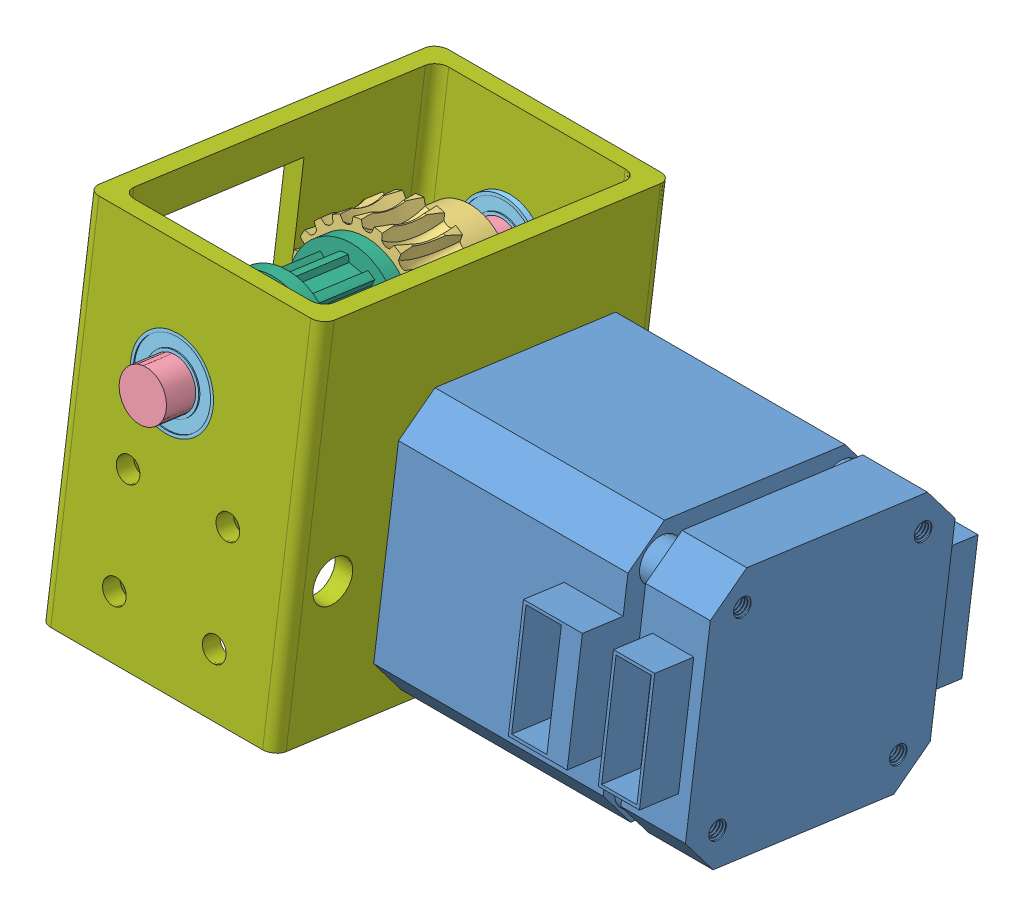
SolidWorks assembly Asm_42Driver_90Degree, configuration 默认. Lengths in mm.
Overall size (98.8 67.62 71.02).
8 component instances, 7 part files, 16 mates.
Components (placement in the parent):
- Part_42Motor-1: Part_42Motor [默认] at (65.4672 -14.0309 56.4881) x (0 0.990656 -0.136383) z (0 0.136383 0.990656) size (42 76 55.7)
- Part_Shaft_1Modulus_1Teeth_42SMotor-1: Part_Shaft_1Modulus_1Teeth_42SMotor [默认] at (-21.5328 3.9089 32.8203) x (1 0 0) z (0 0.681581 -0.731743) size (33.1 17.69 17.84)
- Part_Turbine_1Modulus_20Teeth_42SMotor-1: Part_Turbine_1Modulus_20Teeth_42SMotor [默认] at (-10.5328 22.4226 35.3187) x (0 -0.990656 0.136383) z (1 0 0) size (29.84 18 44.58)
- Part_Axis_8mm_Turbine_Rocker-1: Part_Axis_8mm_Turbine_Rocker [默认] at (-10.5328 17.922 2.627) x (0.931599 0.360092 -0.049574) z (0 0.136383 0.990656) size (8 17.7 70)
- Part_Bearing_MR148ZZ-1: Part_Bearing_MR148ZZ [默认] at (-10.5328 19.1494 11.5429) x (0 -0.136383 -0.990656) z (0.425184 0.89665 -0.123441) size (4 14 14)
- Part_Bearing_MR148ZZ-2: Part_Bearing_MR148ZZ [默认] at (-10.5328 26.7869 67.0197) x (0 -0.136383 -0.990656) z (-0.945462 0.322689 -0.044424) size (4 14 14)
- Part_SyncWheel_XL10AF_Axis_8mm-2: Part_SyncWheel_XL10AF_Axis_8mm [默认] at (-10.5328 24.2638 48.6925) x (0 -0.136383 -0.990656) z (0.128031 -0.982503 0.13526) size (16 19 19)
- Part_Flange_42Motor-1: Part_Flange_42Motor [默认] at (-27.5328 -22.013 13.172) x (0 0.990656 -0.136383) z (0 -0.136383 -0.990656) size (60 40 60)
Mates (geometry in assembly coordinates):
- 重合8: coincident aligned: line of Part_Shaft_1Modulus_1Teeth_42SMotor-1 through (-21.5328 3.9089 32.8203) axis (1 0 0); line of Part_Turbine_1Modulus_20Teeth_42SMotor-1 through (-29.181 3.9089 32.8203) axis (1 0 0)
- 同心5: concentric anti-aligned: cylinder of Part_Shaft_1Modulus_1Teeth_42SMotor-1 through (8.4672 3.9089 32.8203) axis (-1 0 0) radius 2.5; cylinder of Part_42Motor-1 through (-10.5328 3.9089 32.8203) axis (1 0 0) radius 2.5
- 距离7: distance = 4 mm anti-aligned: plane of Part_Shaft_1Modulus_1Teeth_42SMotor-1 through (8.4672 3.9089 32.8203) normal (1 0 0); plane of Part_42Motor-1 through (4.4672 -14.0309 56.4881) normal (-1 0 0)
- 平行6: parallel aligned: plane of Part_42Motor-1 through (12.4672 -14.3103 14.1304) normal (0 -0.136383 -0.990656); plane of Part_Turbine_1Modulus_20Teeth_42SMotor-1 through (-10.5328 21.0588 25.4121) normal (0 -0.136383 -0.990656)
- 同心6: concentric anti-aligned: cylinder of Part_Turbine_1Modulus_20Teeth_42SMotor-1 through (-10.5328 21.0588 25.4121) axis (0 0.136383 0.990656) radius 4; cylinder of Part_Axis_8mm_Turbine_Rocker-1 through (-10.5328 27.4688 71.9729) axis (0 -0.136383 -0.990656) radius 4
- 同心7: concentric anti-aligned: cylinder of Part_Axis_8mm_Turbine_Rocker-1 through (-10.5328 27.4688 71.9729) axis (0 -0.136383 -0.990656) radius 4; cylinder of Part_Bearing_MR148ZZ-2 through (-10.5328 26.2413 63.057) axis (0 0.136383 0.990656) radius 4
- 同心8: concentric anti-aligned: cylinder of Part_Axis_8mm_Turbine_Rocker-1 through (-10.5328 27.4688 71.9729) axis (0 -0.136383 -0.990656) radius 4; cylinder of Part_Bearing_MR148ZZ-1 through (-10.5328 18.6039 7.5803) axis (0 0.136383 0.990656) radius 4
- 同心9: concentric anti-aligned: cylinder of Part_Axis_8mm_Turbine_Rocker-1 through (-10.5328 27.4688 71.9729) axis (0 -0.136383 -0.990656) radius 4; cylinder of Part_SyncWheel_XL10AF_Axis_8mm-1 through (-10.5328 22.7636 37.7953) axis (0 0.136383 0.990656) radius 4
- 距离8: distance = 5 mm aligned: plane of Part_Axis_8mm_Turbine_Rocker-1 through (-10.5328 17.922 2.627) normal (0 -0.136383 -0.990656); plane of Part_Bearing_MR148ZZ-1 through (-10.5328 18.6039 7.5803) normal (0 -0.136383 -0.990656)
- 重合14: coincident anti-aligned: plane of Part_42Motor-1 through (12.4672 -14.0309 56.4881) normal (-1 0 0); plane of Part_Flange_42Motor-1 through (12.4672 45.3366 62.4471) normal (1 0 0)
- 同心10: concentric anti-aligned: circle of Part_42Motor-1; cylinder of Part_Flange_42Motor-1 through (-27.5338 -13.5602 19.579) axis (1 0 0) radius 2.5
- 同心11: concentric anti-aligned: circle of Part_42Motor-1; cylinder of Part_Flange_42Motor-1 through (-27.5338 17.1501 15.3512) axis (1 0 0) radius 2.5
- 同心12: concentric anti-aligned: cylinder of Part_Bearing_MR148ZZ-1 through (-10.5328 18.6039 7.5803) axis (0 0.136383 0.990656) radius 7; cylinder of Part_Flange_42Motor-1 through (-10.5328 26.7869 67.0197) axis (0 -0.136383 -0.990656) radius 7
- 重合15: coincident aligned: plane of Part_Bearing_MR148ZZ-1 through (-10.5328 18.6039 7.5803) normal (0 -0.136383 -0.990656); plane of Part_Flange_42Motor-1 through (10.4672 37.4264 4.989) normal (0 -0.136383 -0.990656)
- 重合16: coincident aligned: plane of Part_Bearing_MR148ZZ-2 through (-10.5328 26.7869 67.0197) normal (0 0.136383 0.990656); plane of Part_Flange_42Motor-1 through (-25.5328 45.6093 64.4284) normal (0 0.136383 0.990656)
- 重合17: coincident anti-aligned: plane of Part_Turbine_1Modulus_20Teeth_42SMotor-1 through (-10.5328 22.4226 35.3187) normal (0 0.136383 0.990656); plane of Part_SyncWheel_XL10AF_Axis_8mm-2 through (-10.5328 22.4226 35.3187) normal (0 -0.136383 -0.990656)
